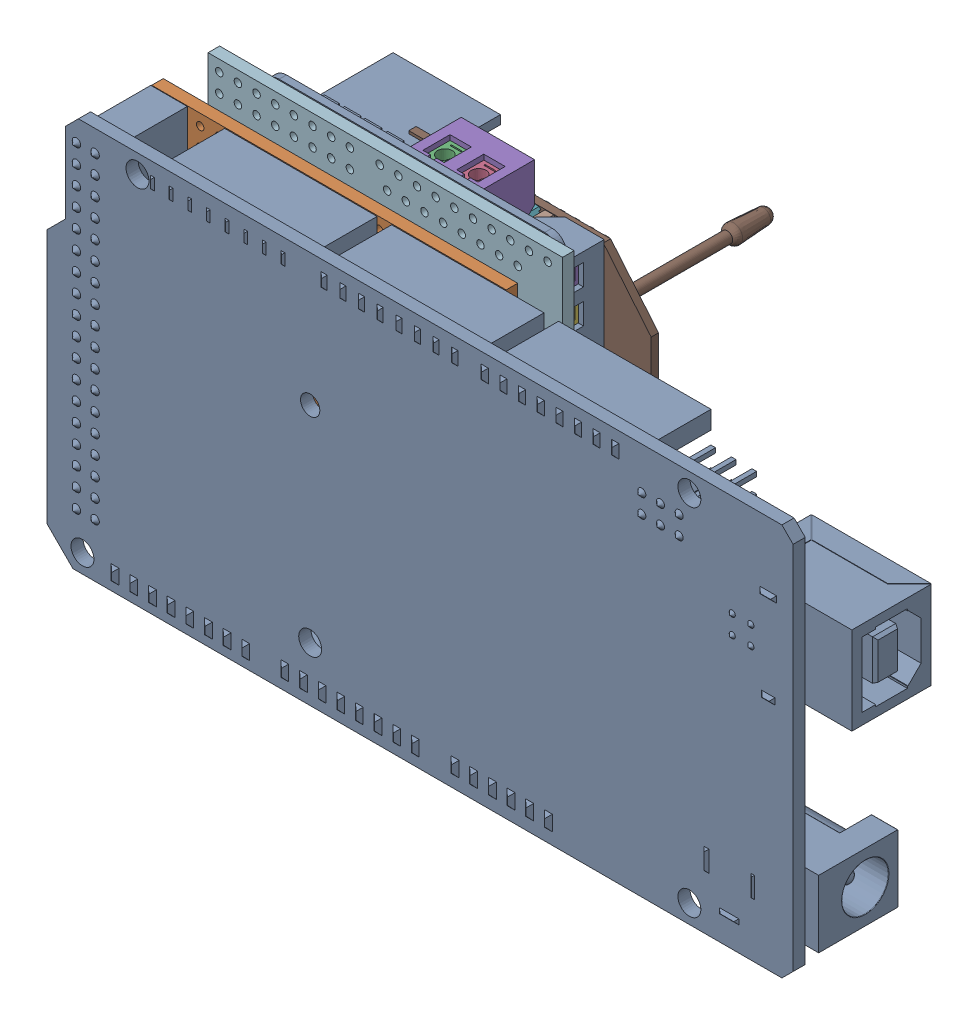
SolidWorks assembly BoardAssembly, configuration Default. Lengths in mm.
Overall size (107.95 53.42 59.57).
5 component instances, 4 part files, 12 mates.
Components (placement in the parent):
- ArduinoMega-1: ArduinoMega [Default] at origin size (107.95 53.42 12.95)
- dual-tb9051ftg-motor-driver-shield-1: dual-tb9051ftg-motor-driver-shield [Default] at (1.524 -25.8699 -8.5598) x (-1 0 0) z (0 0 -1) size (48.26 51.31 7.68)
- Xbee w-headers-1: Xbee w-headers [Default] at (-10.7707 -2.7081 -39.7578) x (1 0 0) z (0 1 0) size (33 30 25)
- dual-tb9051ftg-motor-driver-shield-2: dual-tb9051ftg-motor-driver-shield [Default] at (1.524 -25.8699 -16.2346) x (-1 0 0) z (0 0 -1) size (48.26 51.31 7.68)
- L298N-1: L298N [Default] at (4.2158 -10.9912 -7.432) x (0 1 0) z (-1 0 0) size (39.39 19 41.67)
Mates (geometry in assembly coordinates):
- Coincident1: coincident anti-aligned: plane of ArduinoMega-1 through (-46.736 -20.7899 -8.5598) normal (0 0 -1); plane of dual-tb9051ftg-motor-driver-shield-1 through (1.524 -25.8699 -8.5598) normal (0 0 1)
- Coincident2: coincident aligned: plane of ArduinoMega-1 through (-46.736 25.4889 -8.5598) normal (-1 0 0); plane of dual-tb9051ftg-motor-driver-shield-1 through (-46.736 -25.8699 -10.1346) normal (-1 0 0)
- Coincident3: coincident aligned: plane of ArduinoMega-1 through (-36.6776 25.4381 -8.5598) normal (0 1 0); plane of dual-tb9051ftg-motor-driver-shield-1 through (-46.736 25.4381 -10.1346) normal (0 1 0)
- Coincident4: coincident anti-aligned: plane of dual-tb9051ftg-motor-driver-shield-1 through (1.524 -25.8699 -16.2346) normal (0 0 -1); plane of dual-tb9051ftg-motor-driver-shield-2 through (1.524 -25.8699 -16.2346) normal (0 0 1)
- Concentric1: concentric aligned: cylinder of dual-tb9051ftg-motor-driver-shield-1 through (-42.164 12.2841 -10.1346) axis (0 0 1) radius 1.0922; cylinder of dual-tb9051ftg-motor-driver-shield-2 through (-42.164 12.2841 -17.8094) axis (0 0 1) radius 1.0922
- Concentric2: concentric aligned: cylinder of dual-tb9051ftg-motor-driver-shield-1 through (-42.164 -12.7159 -10.1346) axis (0 0 1) radius 1.0922; cylinder of dual-tb9051ftg-motor-driver-shield-2 through (-42.164 -12.7159 -17.8094) axis (0 0 1) radius 1.0922
- Coincident5: coincident: plane of dual-tb9051ftg-motor-driver-shield-2 through (1.524 -25.8699 -23.9094) normal (0 0 -1); plane of L298N-1 through (-8.5848 5.9392 -23.9094) normal (0 0 1)
- Coincident10: coincident: plane of dual-tb9051ftg-motor-driver-shield-2 through (-46.736 -25.8699 -17.8094) normal (-1 0 0); plane of L298N-1 through (-46.736 17.4795 -24.9094) normal (-1 0 0)
- Width2: width aligned: plane of L298N-1 through (-44.736 19.4795 -24.9094) normal (0 1 0); plane of dual-tb9051ftg-motor-driver-shield-2 through (-44.736 -19.9113 -24.9094) normal (0 -1 0); plane of L298N-1 through (-46.736 25.4381 -17.8094) normal (0 1 0); plane of dual-tb9051ftg-motor-driver-shield-2 through (1.524 -25.8699 -17.8094) normal (0 -1 0)
- Coincident11: coincident: plane of Xbee w-headers-1 through (-36.8042 8.83 -32.4094) normal (0 0 1); plane of L298N-1 through (-19.7667 8.2833 -32.4094) normal (0 0 -1)
- Width3: width: plane of Xbee w-headers-1 through (-37.5823 -13.2667 -35.4094) normal (0 -1 0); plane of L298N-1 through (-37.5823 11.7333 -35.4094) normal (0 1 0); plane of Xbee w-headers-1 through (-40.5823 -11.7086 -42.9094) normal (0 1 0); plane of L298N-1 through (-33.6021 10.1752 -42.9094) normal (0 -1 0)
- Coincident12: coincident anti-aligned: plane of Xbee w-headers-1 through (-37.5823 11.7333 -35.4094) normal (-1 0 0); plane of L298N-1 through (-37.5823 -14.0924 -7.5041) normal (1 0 0)
